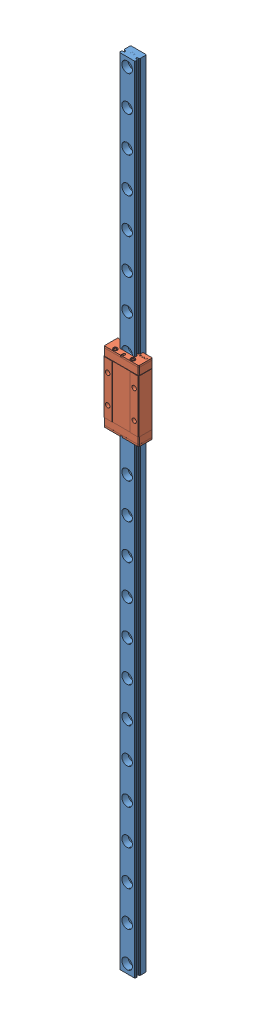
SolidWorks assembly X-Axis_Hiwin Rail MGN09H1R450Z0HM, configuration Default. Lengths in mm.
2 component instances, 2 part files, 3 mates.
Components (placement in the parent):
- MGN09H1R450Z0HM_FILE(2)-1: MGN09H1R450Z0HM_FILE(2) [Default] at origin size (9 450 6.5)
- MGN09H1R450Z0HM_FILE-1: MGN09H1R450Z0HM_FILE [Default] at (0 250.011 0) size (20 45.58 8)
Mates (geometry in assembly coordinates):
- Concentric1: concentric aligned: cylinder of MGN09H1R450Z0HM_FILE(2)-1 through (-3.5197 450 4.4558) axis (0 -1 0) radius 0.45; cylinder of MGN09H1R450Z0HM_FILE-1 through (-3.5197 317.852 4.4558) axis (0 -1 0) radius 0.45
- Concentric2: concentric aligned: cylinder of MGN09H1R450Z0HM_FILE(2)-1 through (3.5197 450 4.4558) axis (0 -1 0) radius 0.45; cylinder of MGN09H1R450Z0HM_FILE-1 through (3.5197 317.852 4.4558) axis (0 -1 0) radius 0.45
- LimitDistance1: limit distance = 265.012 mm aligned: plane of MGN09H1R450Z0HM_FILE-1 through (-9.8 265.012 9.7) normal (0 -1 0); plane of MGN09H1R450Z0HM_FILE(2)-1 through (-4.5 0 6.5) normal (0 -1 0)
